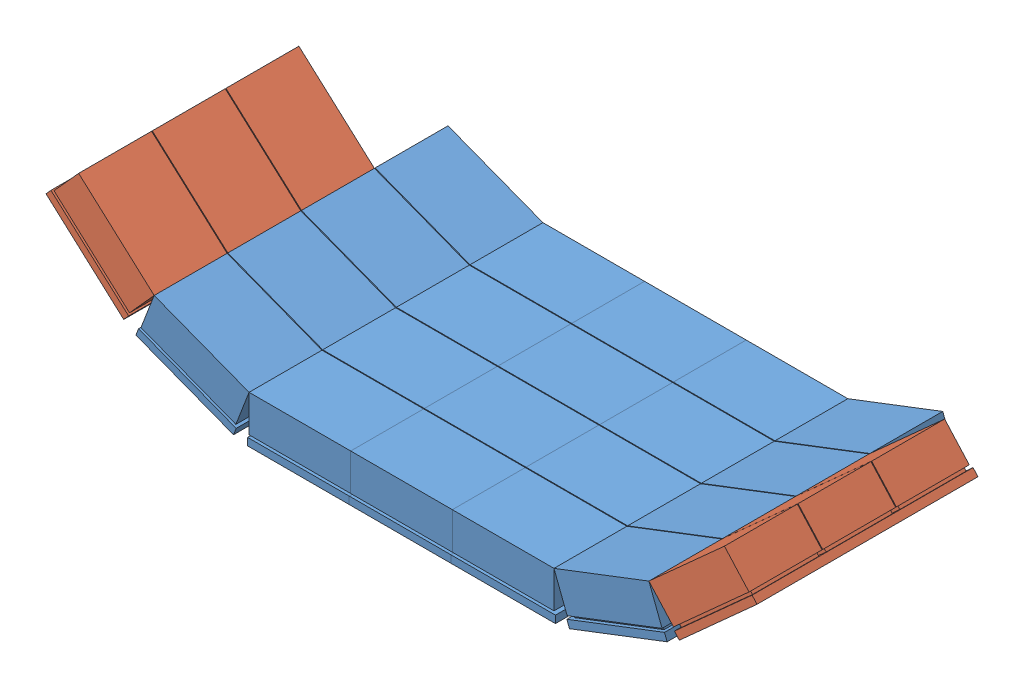
SolidWorks assembly Detector_posterial, configuration Default. Lengths in mm.
Overall size (482.7 103.57 200).
7 component instances, 2 part files, 17 mates.
Components (placement in the parent):
- 1Detector-1: 1Detector [Default] at (83.9721 85.3161 150.6758) size (71 32 200)
- 1Detector-2: 1Detector [Default] at (152.9721 85.3161 150.6758) size (71 32 200)
- 1Detector-3: 1Detector [Default] at (14.9721 85.3161 150.6758) size (71 32 200)
- 1Detector-4: 1Detector [Default] at (-63.2042 99.8052 150.6758) x (0.93358 -0.358368 0) z (0 0 1) size (71 32 200)
- 1Detector-5: 1Detector [Default] at (231.1484 99.8052 150.6758) x (0.93358 0.358368 0) z (0 0 1) size (71 32 200)
- 1Detector_3modules-1: 1Detector_3modules [Default] at (-130.9957 141.3479 175.6758) x (0.743145 -0.669131 0) z (0 0 1) size (71 32 150)
- 1Detector_3modules-2: 1Detector_3modules [Default] at (298.9398 141.3479 175.6758) x (0.743145 0.669131 0) z (0 0 1) size (71 32 150)
Mates (geometry in assembly coordinates):
- Coincident2: coincident anti-aligned: line of 1Detector-1 through (118.4721 117.3161 250.6758) axis (0 0 -1); line of 1Detector-2 through (118.4721 117.3161 201.1758) axis (0 0 1)
- Coincident19: coincident aligned: line of 1Detector-1 through (49.4721 117.3161 250.6758) axis (1 0 0); line of 1Detector-2 through (118.4721 117.3161 250.6758) axis (1 0 0)
- Coincident4: coincident: point of 1Detector-1; point of 1Detector-2
- Coincident5: coincident anti-aligned: line of 1Detector-1 through (49.4721 117.3161 201.1758) axis (0 0 1); line of 1Detector-3 through (49.4721 117.3161 250.6758) axis (0 0 -1)
- Coincident20: coincident aligned: line of 1Detector-1 through (49.4721 117.3161 250.6758) axis (1 0 0); line of 1Detector-3 through (-19.5279 117.3161 250.6758) axis (1 0 0)
- Coincident7: coincident: point of 1Detector-1; point of 1Detector-3
- Coincident8: coincident anti-aligned: line of 1Detector-2 through (49.4721 117.3161 250.6758) axis (0 0 -1); line of 1Detector-5 through (49.4721 117.3161 201.1758) axis (0 0 1)
- Angle3: planar angle = 2.775074 rad anti-aligned: line of 1Detector-2 through (118.4721 117.3161 250.6758) axis (1 0 0); line of 1Detector-5 through (187.4721 117.3161 250.6758) axis (0.93358 0.358368 0)
- Coincident10: coincident anti-aligned: line of 1Detector-3 through (118.4721 117.3161 201.1758) axis (0 0 1); line of 1Detector-4 through (118.4721 117.3161 250.6758) axis (0 0 -1)
- Angle4: planar angle = 2.775074 rad anti-aligned: line of 1Detector-4 through (-83.945 142.0435 250.6758) axis (0.93358 -0.358368 0); line of 1Detector-3 through (-19.5279 117.3161 250.6758) axis (1 0 0)
- Coincident12: coincident: point of 1Detector-3; point of 1Detector-4
- Coincident13: coincident anti-aligned: line of 1Detector-4 through (182.8891 92.5887 201.1758) axis (0 0 1); line of 1Detector_3modules-1 through (182.8891 92.5887 250.6758) axis (0 0 -1)
- Angle5: planar angle = 2.775074 rad anti-aligned: line of 1Detector_3modules-1 through (-135.222 188.2135 250.6758) axis (0.743145 -0.669131 0); line of 1Detector-4 through (-83.945 142.0435 250.6758) axis (0.93358 -0.358368 0)
- Coincident15: coincident: point of 1Detector-4; point of 1Detector_3modules-1
- Coincident16: coincident anti-aligned: line of 1Detector-5 through (-14.945 92.5887 250.6758) axis (0 0 -1); line of 1Detector_3modules-2 through (-14.945 92.5887 201.1758) axis (0 0 1)
- Angle6: planar angle = 2.775074 rad anti-aligned: line of 1Detector-5 through (187.4721 117.3161 250.6758) axis (0.93358 0.358368 0); line of 1Detector_3modules-2 through (251.8891 142.0435 250.6758) axis (0.743145 0.669131 0)
- Coincident18: coincident: point of 1Detector-5; point of 1Detector_3modules-2
